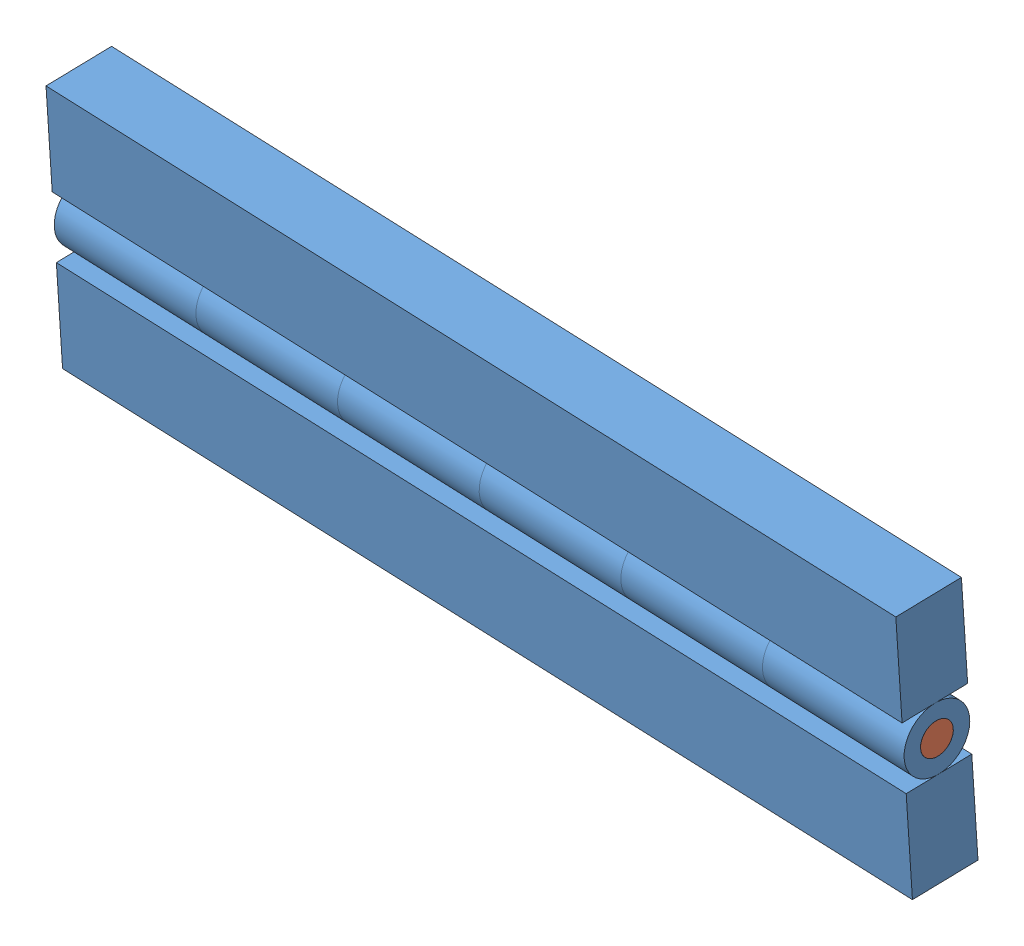
SolidWorks assembly hinge assembly, configuration Default. Lengths in mm.
Overall size (140.38 40.55 18.03).
3 component instances, 2 part files, 4 mates.
Components (placement in the parent):
- ha1-1: ha1 [Default] at (-38.5403 -36.6596 41.501) x (-0.999218 0 -0.039538) z (0.039459 0.063101 -0.997227) size (140 25 10)
- Part2-1: Part2 [Default] at (-108.3195 -23.869 34.5353) x (0.999218 0 0.039538) z (0.039426 -0.075219 -0.996387) size (140 5 5)
- ha1-2: ha1 [Default] at (-38.6027 -11.7095 43.0773) x (0.999218 0 0.039538) z (0.039459 0.063101 -0.997227) size (140 25 10)
Mates (geometry in assembly coordinates):
- Concentric1: concentric anti-aligned: cylinder of ha1-1 through (-96.6619 -23.869 34.9966) axis (-0.999218 0 -0.039538) radius 2.5; cylinder of Part2-1 through (-38.3742 -23.869 37.303) axis (0.999218 0 0.039538) radius 2.5
- Coincident1: coincident aligned: cylinder of Part2-1 through (-38.3742 -23.869 37.303) axis (0.999218 0 0.039538) radius 2.5; circle of ha1-2
- Coincident3: coincident anti-aligned: plane of ha1-1 through (-85.1705 -36.6596 39.6559) normal (0.999218 0 0.039538); plane of ha1-2 through (-85.2329 -11.7095 41.2322) normal (-0.999218 0 -0.039538)
- Coincident4: coincident aligned: plane of Part2-1 through (-108.3195 -23.869 34.5353) normal (-0.999218 0 -0.039538); plane of ha1-2 through (-108.5667 -4.2244 40.7825) normal (-0.999218 0 -0.039538)
